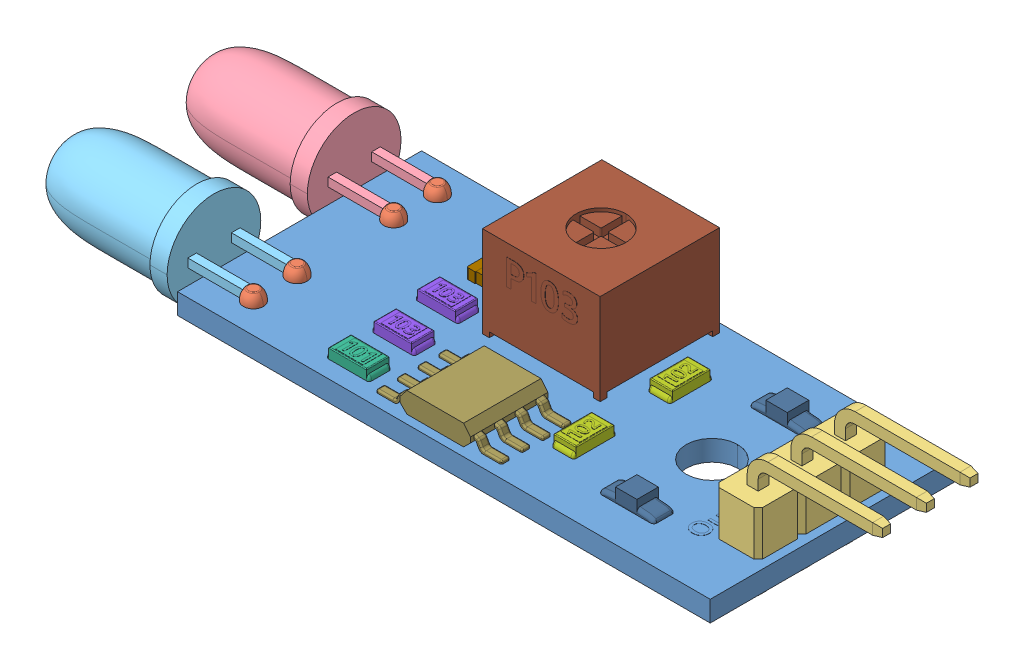
SolidWorks assembly IRsensors.STEP, configuration Default. Lengths in mm.
Overall size (46.26 8.05 14.2).
24 component instances, 12 part files, 0 mates.
Components (placement in the parent):
- IRboard.STEP-1: IRboard.STEP [Default] at origin size (31 1.21 14.2)
- solder.STEP-1: solder.STEP [Default] at (13.7543 0 -2.5042) x (-0.837169 0 -0.546944) z (-0.546944 0 0.837169) size (1.17 0.65 1.17)
- 90headerMale.STEP-1: 90headerMale.STEP [Default] at (13.73 1.2 -2.54) x (0 0 1) z (-1 0 0) size (2.54 7.1 8.75)
- 90headerMale.STEP-2: 90headerMale.STEP [Default] at (13.73 1.2 0) x (0 0 1) z (-1 0 0) size (2.54 7.1 8.75)
- 90headerMale.STEP-3: 90headerMale.STEP [Default] at (13.73 1.2 2.54) x (0 0 1) z (-1 0 0) size (2.54 7.1 8.75)
- solder.STEP-2: solder.STEP [Default] at (13.7543 0 0.0358) x (-0.837169 0 -0.546944) z (-0.546944 0 0.837169) size (1.17 0.65 1.17)
- solder.STEP-3: solder.STEP [Default] at (13.7543 0 2.5758) x (-0.837169 0 -0.546944) z (-0.546944 0 0.837169) size (1.17 0.65 1.17)
- blackLEDIRsensor.STEP-1: blackLEDIRsensor.STEP [Default] at (-16.4 1.45 -4.08) x (0 0 1) z (0 -1 0) size (5.45 12.45 5.45)
- whiteLEDIRsensor.STEP-1: whiteLEDIRsensor.STEP [Default] at (-16.4 1.45 4.08) x (0 0 -1) z (0 1 0) size (5.45 12.45 5.45)
- solder.STEP-4: solder.STEP [Default] at (-12.8311 1.2 -5.3527) size (1.17 0.65 1.17)
- solder.STEP-5: solder.STEP [Default] at (-12.8311 1.2 -2.8127) size (1.17 0.65 1.17)
- solder.STEP-6: solder.STEP [Default] at (-12.8311 1.2 5.3527) size (1.17 0.65 1.17)
- solder.STEP-7: solder.STEP [Default] at (-12.8311 1.2 2.8127) size (1.17 0.65 1.17)
- smdResistor101.STEP-1: smdResistor101.STEP [Default] at (-6.6 1.2 5.45) size (2.53 0.63 1.31)
- smdResistor102.STEP-1: smdResistor102.STEP [Default] at (3.85 1.2 2.8) x (0 0 -1) z (1 0 0) size (2.53 0.63 1.31)
- smdResistor103.STEP-1: smdResistor103.STEP [Default] at (-6.6027 1.2 2.8237) size (2.53 0.63 1.31)
- smdResistor103.STEP-2: smdResistor103.STEP [Default] at (-6.6333 1.5163 0.25) size (2.53 0.63 1.31)
- smdResistor102.STEP-2: smdResistor102.STEP [Default] at (3.85 1.2 -2.8) x (0 0 -1) z (1 0 0) size (2.53 0.63 1.31)
- smdceramiccapacitor.STEP-1: smdceramiccapacitor.STEP [Default] at (-6.6378 1.2 -2.6096) size (2.52 0.61 1.3)
- smdceramiccapacitor.STEP-2: smdceramiccapacitor.STEP [Default] at (-6.6378 1.2 -5.1496) size (2.52 0.61 1.3)
- smdLED.STEP-1: smdLED.STEP [Default] at (8.5086 1.25 -4.375) size (3.23 0.86 1.26)
- smdLED.STEP-2: smdLED.STEP [Default] at (8.5086 1.25 4.375) size (3.23 0.86 1.26)
- smdTrimmerP103.STEP-1: smdTrimmerP103.STEP [Default] at (-1.0819 1.5 -3.125) size (6.85 5.3 6.96)
- smdChip8pin.STEP-1: smdChip8pin.STEP [Default] at (-1.0012 1.9 2.1) size (7.3 1.22 4.5)
